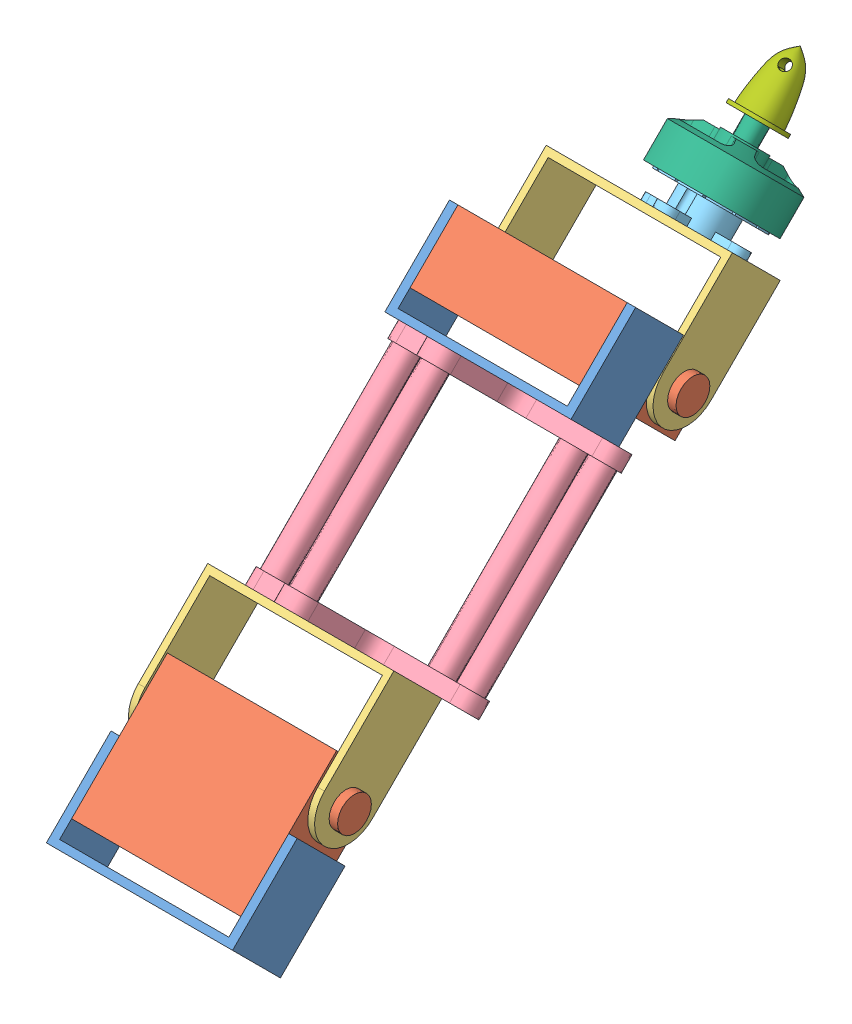
SolidWorks assembly servomotor, configuration Default. Lengths in mm.
Overall size (71 149.1 199.17).
10 component instances, 7 part files, 27 mates.
Components (placement in the parent):
- servo2-1: servo2 [Default] at (0.0164 -18.0661 39.3131) x (1 0 0) z (0 0.707107 0.707107) size (55 27 20)
- servo3-1: servo3 [Default] at (0.0164 -6.0453 13.1501) x (1 0 0) z (0 0.707107 0.707107) size (60 40 20)
- servo1-1: servo1 [Default] at (0.0164 29.5984 -8.3514) x (1 0 0) z (0 0.707107 0.707107) size (55 39 20)
- Part1-1: Part1 [Default] at (7.5164 68.1357 -53.9598) x (0 0.707107 0.707107) z (-1 0 0) size (67 64 67)
- servo2-2: servo2 [Default] at (0.0164 67.7822 -60.6773) x (1 0 0) z (0 0.707107 0.707107) size (55 27 20)
- servo3-2: servo3 [Default] at (0.0164 65.6609 -72.6981) x (1 0 0) z (0 0.707107 -0.707107) size (60 40 20)
- servo1-2: servo1 [Default] at (0.0164 86.5857 -108.3418) x (1 0 0) z (0 0.707107 0.707107) size (55 39 20)
- Part2-1: Part2 [Default] at (5.5164 84.4644 -113.2915) x (0 0.707107 0.707107) z (1 0 0) size (30 15 30)
- Part3-1: Part3 [Default] at (5.5164 88.3535 -117.1806) x (0.362213 -0.659091 -0.659091) z (0.932095 0.256124 0.256124) size (33 35.5 33)
- Part4-1: Part4 [Default] at (5.5164 102.4956 -131.3228) x (-0.395149 -0.64956 -0.64956) z (0.918617 -0.279412 -0.279412) size (15 18 15)
Mates (geometry in assembly coordinates):
- Coincident1: coincident anti-aligned: plane of servo2-1 through (25.0164 -6.0453 13.1501) normal (-1 0 0); plane of servo3-1 through (25.0164 22.239 13.1501) normal (1 0 0)
- Distance1: distance = 5 mm anti-aligned: plane of servo2-1 through (0.0164 -16.6519 37.8988) normal (0 0.707107 -0.707107); plane of servo3-1 through (-24.9836 -6.0453 41.4344) normal (0 -0.707107 0.707107)
- Coincident3: coincident aligned: plane of servo2-1 through (-27.4836 -23.7229 30.8278) normal (0 -0.707107 -0.707107); plane of servo3-1 through (0.0164 -6.0453 13.1501) normal (0 -0.707107 -0.707107)
- Tangent1: tangent aligned: cylinder of servo3-1 through (30.0164 8.3852 12.8618) axis (-1 0 0) radius 5; cylinder of servo1-1 through (-27.4836 8.3852 12.8618) axis (1 0 0) radius 5
- Distance2: distance = 0.5 mm anti-aligned: plane of servo1-1 through (25.5164 9.0923 26.2968) normal (-1 0 0); plane of servo3-1 through (25.0164 22.239 13.1501) normal (1 0 0)
- Parallel3: parallel anti-aligned: plane of servo1-1 through (-27.4836 21.1131 -14.0083) normal (0 -0.707107 -0.707107); plane of Part1-1 through (36.5164 29.2449 -8.705) normal (0 0.707107 0.707107)
- Concentric4: concentric anti-aligned: cylinder of servo1-1 through (-4.9836 -1.5143 15.6902) axis (0 0.707107 -0.707107) radius 1.5; cylinder of Part1-1 through (-4.9836 29.2449 -15.0689) axis (0 -0.707107 0.707107) radius 2
- Coincident6: coincident anti-aligned: plane of servo1-1 through (0.0164 29.5984 -8.3514) normal (0 0.707107 -0.707107); plane of Part1-1 through (7.5164 26.0629 -11.887) normal (0 -0.707107 0.707107)
- Parallel5: parallel aligned: plane of Part1-1 through (36.5164 74.4997 -53.9598) normal (0 0.707107 0.707107); plane of servo2-2 through (-27.4836 76.2675 -55.0205) normal (0 0.707107 0.707107)
- Concentric8: concentric aligned: cylinder of Part1-1 through (-4.9836 68.1357 -53.9598) axis (0 0.707107 -0.707107) radius 2; cylinder of servo2-2 through (-4.9836 71.3177 -57.1418) axis (0 0.707107 -0.707107) radius 1.5
- Coincident9: coincident anti-aligned: plane of Part1-1 through (7.5164 71.3177 -57.1418) normal (0 0.707107 -0.707107); plane of servo2-2 through (0.0164 67.7822 -60.6773) normal (0 -0.707107 0.707107)
- Distance3: distance = 5 mm anti-aligned: plane of servo3-2 through (0.0164 65.6609 -72.6981) normal (0 -0.707107 0.707107); plane of servo2-2 through (0.0164 69.1964 -62.0915) normal (0 0.707107 -0.707107)
- Coincident11: coincident anti-aligned: plane of servo2-2 through (25.0164 79.803 -86.8403) normal (-1 0 0); plane of servo3-2 through (25.0164 65.6609 -100.9824) normal (1 0 0)
- Coincident12: coincident aligned: plane of servo2-2 through (-27.4836 76.2675 -55.0205) normal (0 0.707107 0.707107); plane of servo3-2 through (-24.9836 93.9451 -72.6981) normal (0 0.707107 0.707107)
- Tangent2: tangent aligned: cylinder of servo3-2 through (30.0164 65.3725 -87.1286) axis (-1 0 0) radius 5; cylinder of servo1-2 through (-27.4836 65.3725 -87.1286) axis (1 0 0) radius 5
- Distance4: distance = 0.5 mm anti-aligned: plane of servo1-2 through (-25.4836 66.0796 -73.6936) normal (1 0 0); plane of servo3-2 through (-24.9836 65.6609 -100.9824) normal (-1 0 0)
- Concentric9: concentric anti-aligned: cylinder of servo1-2 through (15.0164 55.473 -84.3002) axis (0 0.707107 -0.707107) radius 1.5; cylinder of Part2-1 through (15.0164 84.4644 -113.2915) axis (0 -0.707107 0.707107) radius 1.5
- Parallel6: parallel aligned: plane of servo1-2 through (-27.4836 78.1005 -113.9986) normal (0 -0.707107 -0.707107); plane of Part2-1 through (5.5164 80.9289 -113.9986) normal (0 -0.707107 -0.707107)
- Coincident16: coincident anti-aligned: plane of servo1-2 through (0.0164 86.5857 -108.3418) normal (0 0.707107 -0.707107); plane of Part2-1 through (5.5164 83.0502 -111.8773) normal (0 -0.707107 0.707107)
- Concentric10: concentric anti-aligned: cylinder of Part2-1 through (5.5164 93.6568 -122.4839) axis (0 -0.707107 0.707107) radius 1.5; cylinder of Part3-1 through (5.5164 84.4644 -113.2915) axis (0 0.707107 -0.707107) radius 1.5
- Coincident17: coincident anti-aligned: plane of Part2-1 through (5.5164 96.4852 -119.6555) normal (0 0.707107 -0.707107); plane of Part3-1 through (5.5164 93.6568 -122.4839) normal (0 -0.707107 0.707107)
- Concentric11: concentric aligned: cylinder of Part3-1 through (5.5164 88.3535 -117.1806) axis (0 -0.707107 0.707107) radius 3; cylinder of Part4-1 through (5.5164 110.2738 -139.1009) axis (0 -0.707107 0.707107) radius 3.5
- Distance5: distance = 5 mm anti-aligned: plane of Part4-1 through (5.5164 101.7885 -130.6157) normal (0 -0.707107 0.707107); plane of Part3-1 through (7.6896 94.2985 -131.0347) normal (0 0.707107 -0.707107)
- Coincident19: coordinate: point of servo3-1; point of assembly
- Angle2: planar angle = 3.141593 rad anti-aligned: plane of servo3-1; plane of servo1-1
- Angle3: planar angle = 1.570796 rad aligned: plane of servo2-1 through (0.0164 1.0258 20.2212) normal (0 0.707107 -0.707107); plane of servo1-1 through (-27.4836 35.2553 0.1339) normal (0 0.707107 0.707107)
- Angle4: planar angle = 1.570796 rad anti-aligned: plane of servo3-2 through (0.0164 79.803 -86.8403) normal (0 0.707107 -0.707107); plane of servo1-2 through (-27.4836 92.2426 -99.8565) normal (0 0.707107 0.707107)
